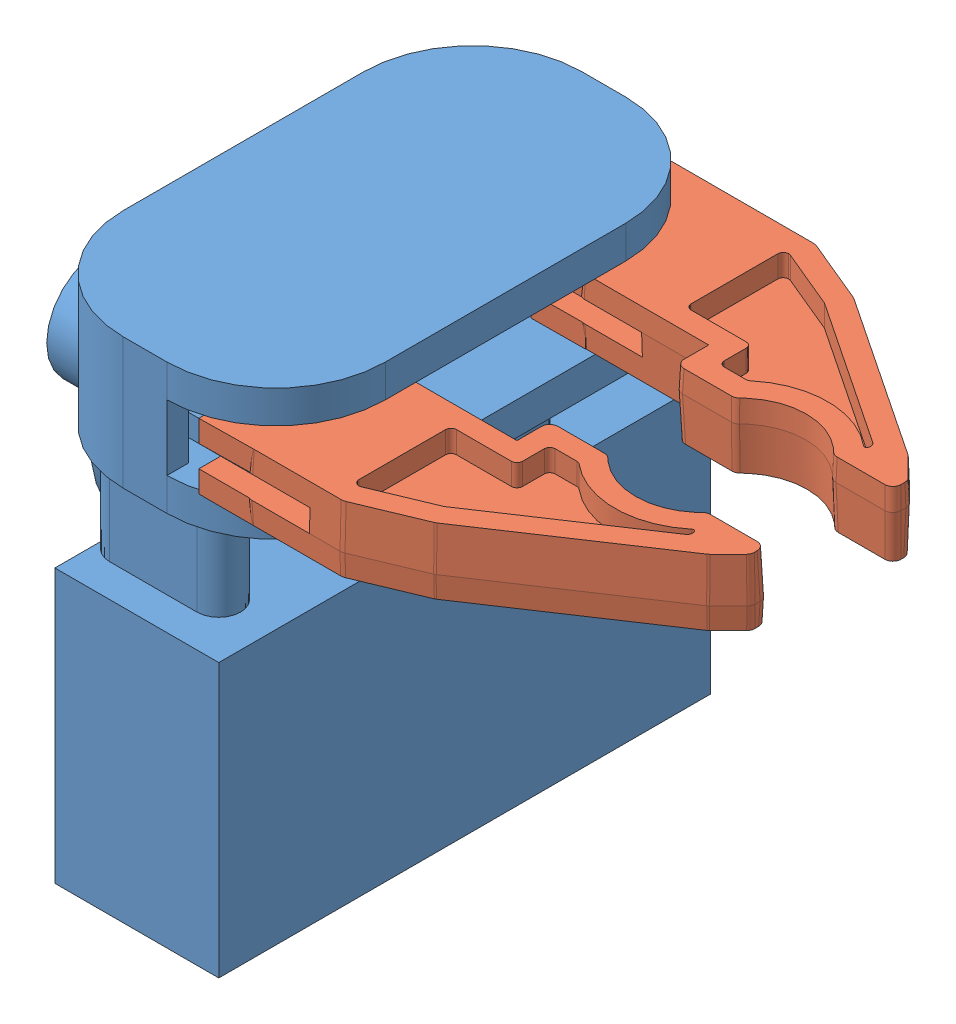
SolidWorks assembly Mirobot_Gripper, configuration 默认. Lengths in mm.
Overall size (67.38 44.2 45).
3 component instances, 2 part files, 4 mates.
Components (placement in the parent):
- 夹子基座-1: 夹子基座 [默认] at (38.1868 14.6192 47.2927) x (0 0 1) z (0 1 0) size (45 37 44.2)
- 夹子手指-2: 夹子手指 [默认] at (59.6748 19.6192 49.206) x (0 0 1) z (0 -1 0) size (44.16 91.99 22)
- 夹子手指-3: 夹子手指 [默认] at (60.9424 21.6292 39.294) x (0 0 -1) z (0 1 0) size (44.16 91.99 22)
Mates (geometry in assembly coordinates):
- 重合6: coincident anti-aligned: plane of 夹子基座-1 through (4.4753 17.6242 33.25) normal (0 1 0); plane of 夹子手指-3 through (36.8538 17.6242 69.6802) normal (0 -1 0)
- 重合7: coincident anti-aligned: plane of 夹子基座-1 through (4.4753 17.6242 33.25) normal (0 1 0); plane of 夹子手指-2 through (35.5862 17.6242 18.8198) normal (0 -1 0)
- 重合8: coincident aligned: plane of 夹子基座-1 through (4.4753 17.6242 23.25) normal (0 0 -1); plane of 夹子手指-3 through (17.6675 7.8261 23.25) normal (0 0 -1)
- 重合9: coincident aligned: plane of 夹子基座-1 through (4.4753 17.6242 65.25) normal (0 0 1); plane of 夹子手指-2 through (16.3999 33.4223 65.25) normal (0 0 1)
